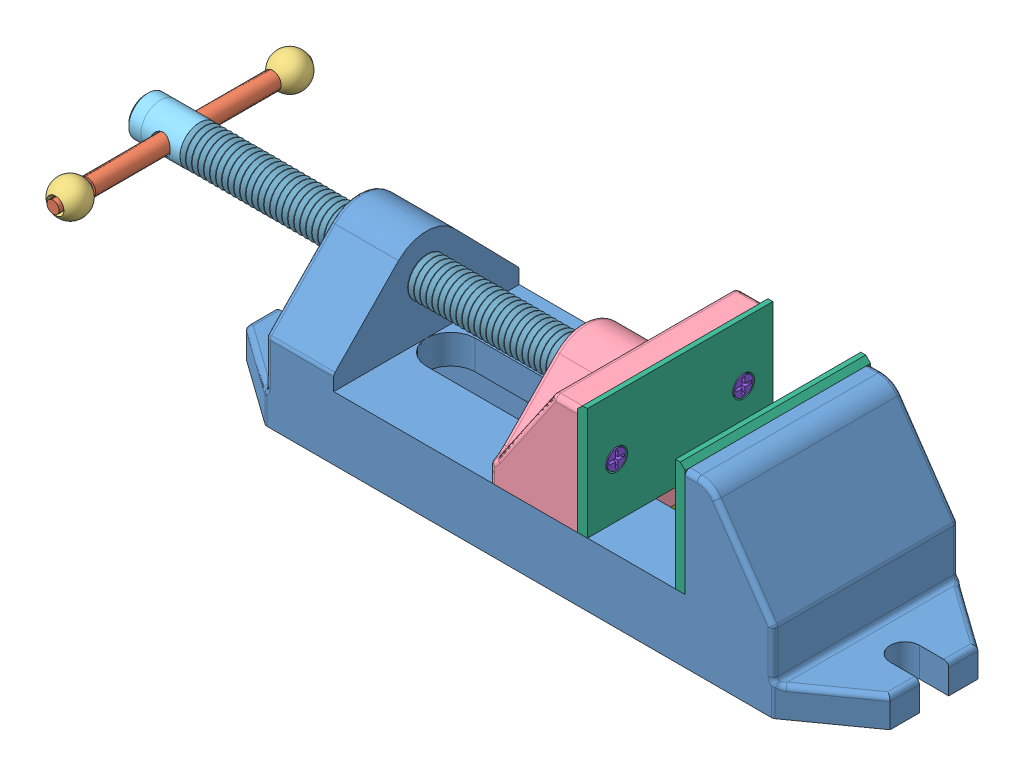
SolidWorks assembly User Library-Vise-1, configuration Default. Lengths in mm.
Overall size (256.38 57.15 82.55).
14 component instances, 9 part files, 35 mates.
Components (placement in the parent):
- User Library-Vise-1_Base-1: User Library-Vise-1_Base [Default] at origin size (209.55 55.56 60.32)
- User Library-Vise-1_Handle-Rod (6)-1: User Library-Vise-1_Handle-Rod (6) [Default] at (-140.4938 38.1 0) size (5.56 5.56 82.55)
- User Library-Vise-1_Handle-Ball (7)-1: User Library-Vise-1_Handle-Ball (7) [Default] at (-140.4938 38.1 35.7188) x (1 0 0) z (0 -1 0) size (11.11 10 11.11)
- User Library-Vise-1_Handle-Ball (7)-2: User Library-Vise-1_Handle-Ball (7) [Default] at (-140.4938 38.1 -35.7188) x (1 0 0) z (0 1 0) size (11.11 10 11.11)
- User Library-Vise-1_Sliding-Jaw-1: User Library-Vise-1_Sliding-Jaw [Default] at (4.7625 11.0871 0.0381) size (28.57 44.48 60.32)
- User Library-Vise-1_Screw-1: User Library-Vise-1_Screw [Default] at (-134.1438 38.1 0) size (161.92 12.7 12.7)
- User Library-Vise-1_Jaw-Plate-1: User Library-Vise-1_Jaw-Plate [Default] at (52.3875 38.8937 0) x (0 0 1) z (-1 0 0) size (60.32 36.51 3.17)
- User Library-Vise-1_Jaw-Plate-2: User Library-Vise-1_Jaw-Plate [Default] at (20.6375 38.8937 0.0381) x (0 0 -1) z (1 0 0) size (60.32 36.51 3.17)
- User Library-Vise-1_Retainer-Plate-1: User Library-Vise-1_Retainer-Plate [Default] at (4.7625 9.5504 0.0381) size (25.4 3.17 22.23)
- flat head screw_ai-5: flat head screw_ai [CR-FHMS 0.138-32x0.375x0.375-N] at (50.7846 38.1 20.6375) size (9.53 6.2 6.2)
- flat head screw_ai-6: flat head screw_ai [CR-FHMS 0.138-32x0.375x0.375-N] at (50.7846 38.1 -20.6375) size (9.53 6.2 6.2)
- flat head screw_ai-7: flat head screw_ai [CR-FHMS 0.138-32x0.375x0.375-N] at (22.2404 38.1 20.6756) x (-1 0 0) z (0 1 0) size (9.53 6.2 6.2)
- flat head screw_ai-8: flat head screw_ai [CR-FHMS 0.138-32x0.375x0.375-N] at (22.2404 38.1 -20.5994) x (-1 0 0) z (0 1 0) size (9.53 6.2 6.2)
- User Library-Vise-1_Retaining-Screw-2: User Library-Vise-1_Retaining-Screw [HBOLT 0.2500-20x1x1-C] at (4.7625 3.1877 0.0381) x (0 1 0) z (0 0 1) size (30.18 12.85 11.13)
Mates (geometry in assembly coordinates):
- Coincident1: coincident anti-aligned: plane of User Library-Vise-1_Jaw-Plate-1 through (53.975 57.15 -30.1625) normal (1 0 0); plane of User Library-Vise-1_Base-1 through (53.975 55.5625 30.1625) normal (-1 0 0)
- Concentric1: concentric aligned: cylinder of User Library-Vise-1_Base-1 through (53.975 38.1 20.6375) axis (-1 0 0) radius 1.3526; cylinder of User Library-Vise-1_Jaw-Plate-1 through (50.8 38.1 20.6375) axis (-1 0 0) radius 1.8986
- Coincident2: coincident anti-aligned: plane of User Library-Vise-1_Base-1 through (53.975 20.6375 30.1625) normal (0 1 0); plane of User Library-Vise-1_Jaw-Plate-1 through (50.8 20.6375 -30.1625) normal (0 -1 0)
- Coincident3: coincident anti-aligned: plane of User Library-Vise-1_Base-1 through (46.0502 0 7.9248) normal (0 0 -1); plane of User Library-Vise-1_Sliding-Jaw-1 through (17.4625 20.6375 7.9248) normal (0 0 1)
- Coincident4: coincident anti-aligned: plane of User Library-Vise-1_Base-1 through (53.975 20.6375 30.1625) normal (0 1 0); plane of User Library-Vise-1_Sliding-Jaw-1 through (-9.525 20.6375 30.2006) normal (0 -1 0)
- Distance1: distance = 50.8 mm anti-aligned: plane of User Library-Vise-1_Sliding-Jaw-1 through (-9.525 20.6375 30.2006) normal (-1 0 0); plane of User Library-Vise-1_Base-1 through (-60.325 25.4 30.1625) normal (1 0 0)
- Coincident5: coincident anti-aligned: plane of User Library-Vise-1_Sliding-Jaw-1 through (19.05 20.6375 30.2006) normal (1 0 0); plane of User Library-Vise-1_Jaw-Plate-2 through (19.05 57.15 30.2006) normal (-1 0 0)
- Concentric2: concentric aligned: cylinder of User Library-Vise-1_Sliding-Jaw-1 through (19.05 38.1 -20.5994) axis (1 0 0) radius 1.3526; circle of User Library-Vise-1_Jaw-Plate-2
- Coincident6: coincident anti-aligned: plane of User Library-Vise-1_Base-1 through (53.975 20.6375 30.1625) normal (0 1 0); plane of User Library-Vise-1_Jaw-Plate-2 through (22.225 20.6375 30.2006) normal (0 -1 0)
- Concentric3: concentric anti-aligned: cylinder of User Library-Vise-1_Handle-Rod (6)-1 through (-140.4938 38.1 -41.275) axis (0 0 1) radius 1.9685; cylinder of User Library-Vise-1_Handle-Ball (7)-2 through (-140.4938 38.1 -45.3362) axis (0 0 -1) radius 1.9812
- Tangent1: tangent anti-aligned: plane of User Library-Vise-1_Handle-Rod (6)-1 through (-140.4938 38.1 -30.1625) normal (0 0 -1); sphere of User Library-Vise-1_Handle-Ball (7)-2
- Concentric4: concentric anti-aligned: cylinder of User Library-Vise-1_Handle-Rod (6)-1 through (-140.4938 38.1 41.275) axis (0 0 -1) radius 1.9685; cylinder of User Library-Vise-1_Handle-Ball (7)-1 through (-140.4938 38.1 45.3362) axis (0 0 1) radius 1.9812
- Tangent2: tangent anti-aligned: plane of User Library-Vise-1_Handle-Rod (6)-1 through (-140.4938 38.1 30.1625) normal (0 0 1); sphere of User Library-Vise-1_Handle-Ball (7)-1
- Coincident7: coincident aligned: plane of User Library-Vise-1_Handle-Rod (6)-1 through (-140.4938 38.1 0) normal (1 0 0); plane of User Library-Vise-1_Handle-Ball (7)-1
- Coincident8: coincident aligned: plane of User Library-Vise-1_Handle-Rod (6)-1 through (-140.4938 38.1 0) normal (1 0 0); plane of User Library-Vise-1_Handle-Ball (7)-2
- Concentric8: concentric anti-aligned: cylinder of User Library-Vise-1_Retainer-Plate-1 through (4.7625 7.9629 0.0381) axis (0 1 0) radius 3.5719; cylinder of User Library-Vise-1_Sliding-Jaw-1 through (4.7625 11.0871 0.0381) axis (0 -1 0) radius 2.5527
- Parallel1: parallel anti-aligned: plane of User Library-Vise-1_Base-1 through (-59.9446 -14.2621 11.9062) normal (0 0 -1); plane of User Library-Vise-1_Retainer-Plate-1 through (17.4625 11.1379 11.1506) normal (0 0 1)
- Coincident12: coincident anti-aligned: plane of User Library-Vise-1_Base-1 through (-59.9446 11.1379 -11.9062) normal (0 -1 0); plane of User Library-Vise-1_Retainer-Plate-1 through (-7.9375 11.1379 -11.0744) normal (0 1 0)
- Coincident131: coincident aligned: cone of User Library-Vise-1_Jaw-Plate-1 through (50.8 38.1 20.6375) axis (1 0 0); cone of flat head screw_ai-5 through (51.3442 38.1 20.6375) axis (1 0 0)
- Coincident141: coincident aligned: cone of User Library-Vise-1_Jaw-Plate-1 through (50.8 38.1 -20.6375) axis (1 0 0); cone of flat head screw_ai-6 through (51.3442 38.1 -20.6375) axis (1 0 0)
- Coincident151: coincident aligned: cone of User Library-Vise-1_Jaw-Plate-2 through (22.225 38.1 20.6756) axis (-1 0 0); cone of flat head screw_ai-7 through (21.6808 38.1 20.6756) axis (-1 0 0)
- Coincident161: coincident aligned: cone of User Library-Vise-1_Jaw-Plate-2 through (22.225 38.1 -20.5994) axis (-1 0 0); cone of flat head screw_ai-8 through (21.6808 38.1 -20.5994) axis (-1 0 0)
- Concentric9: concentric aligned: cylinder of User Library-Vise-1_Base-1 through (-82.55 38.1 0) axis (-1 0 0) radius 5.3581; cylinder of User Library-Vise-1_Screw-1 through (2.3813 38.1 0) axis (-1 0 0) radius 4.3656
- Concentric10: concentric anti-aligned: cylinder of User Library-Vise-1_Handle-Rod (6)-1 through (-140.4938 38.1 30.1625) axis (0 0 -1) radius 2.7781; cylinder of User Library-Vise-1_Screw-1 through (-140.4938 38.1 -6.35) axis (0 0 1) radius 3.175
- Coincident17: coincident aligned: plane of User Library-Vise-1_Handle-Rod (6)-1 through (-140.4938 38.1 0) normal (0 0 1); plane of User Library-Vise-1_Screw-1 through (-134.1438 38.1 0) normal (0 0 1)
- Coincident18: coincident aligned: plane of User Library-Vise-1_Handle-Rod (6)-1 through (-140.4938 38.1 0) normal (0 1 0); plane of User Library-Vise-1_Screw-1 through (-134.1438 38.1 0) normal (0 1 0)
- Coincident19: coincident anti-aligned: plane of User Library-Vise-1_Screw-1 through (10.3187 38.1 0) normal (1 0 0); plane of User Library-Vise-1_Sliding-Jaw-1 through (10.3187 38.1 0.0381) normal (-1 0 0)
- Coincident20: coincident aligned: plane of User Library-Vise-1_Base-1 through (0 0 0) normal (0 0 1); plane of User Library-Vise-1_Screw-1 through (-134.1438 38.1 0) normal (0 0 1)
- Parallel2: parallel anti-aligned: plane of User Library-Vise-1_Jaw-Plate-2 through (20.6375 38.8937 0.0381) normal (0 0 -1); plane of flat head screw_ai-5 through (50.7846 38.1 20.6375) normal (0 0 1)
- Parallel3: parallel anti-aligned: plane of User Library-Vise-1_Jaw-Plate-2 through (20.6375 38.8937 0.0381) normal (0 0 -1); plane of flat head screw_ai-6 through (50.7846 38.1 -20.6375) normal (0 0 1)
- Parallel4: parallel aligned: plane of User Library-Vise-1_Jaw-Plate-2; plane of flat head screw_ai-7 through (22.2404 38.1 20.6756) normal (0 1 0)
- Parallel5: parallel aligned: plane of User Library-Vise-1_Jaw-Plate-2; plane of flat head screw_ai-8 through (22.2404 38.1 -20.5994) normal (0 1 0)
- Concentric121: concentric anti-aligned: cylinder of User Library-Vise-1_Retainer-Plate-1 through (4.7625 7.9629 0.0381) axis (0 1 0) radius 3.5719; cylinder of User Library-Vise-1_Retaining-Screw-2 through (4.7625 3.1877 0.0381) axis (0 -1 0) radius 3.175
- Coincident281: coincident anti-aligned: plane of User Library-Vise-1_Retainer-Plate-1 through (-7.9375 7.9629 -11.0744) normal (0 -1 0); plane of User Library-Vise-1_Retaining-Screw-2 through (-1.6606 7.9629 0.0381) normal (0 1 0)
- Coincident29: coincident aligned: plane of User Library-Vise-1_Retainer-Plate-1 through (4.7625 9.5504 0.0381) normal (0 0 1); plane of User Library-Vise-1_Retaining-Screw-2 through (4.7625 3.1877 0.0381) normal (0 0 1)
